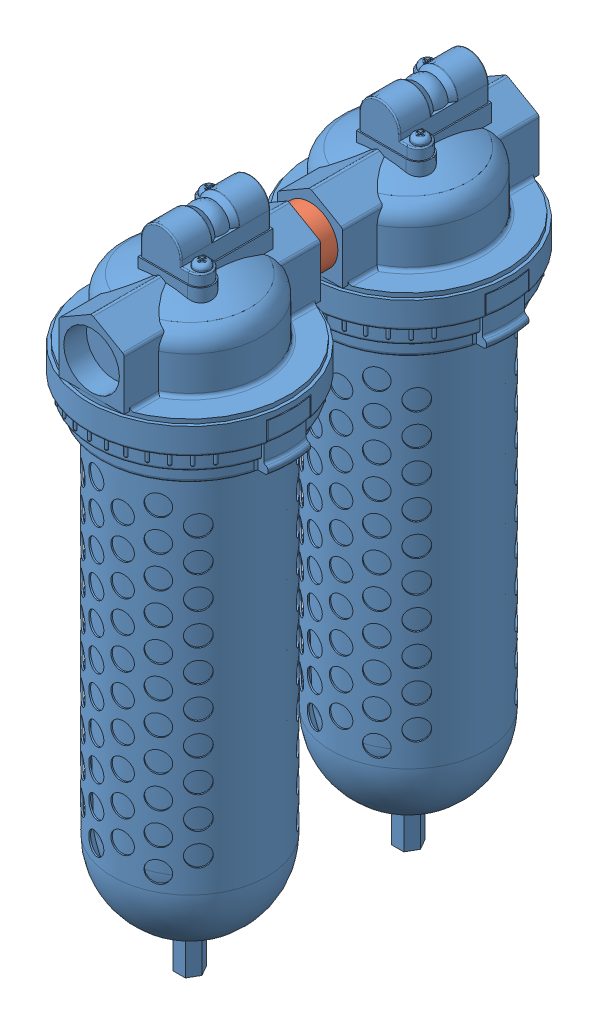
SolidWorks assembly ReadingTech_4P-150-P08-DCi, configuration Default. Lengths in mm.
Overall size (121.86 394.5 252.73).
3 component instances, 2 part files, 3 mates.
Components (placement in the parent):
- ReadingTech_3P150P08Fi-1: ReadingTech_3P150P08Fi [Default] at (-33.0885 -215.021 -0.1977) size (121.86 394.5 121.67)
- ReadingTech_3P150P08Fi-2: ReadingTech_3P150P08Fi [Default] at (-33.0885 -215.021 -131.2617) size (121.86 394.5 121.67)
- ReadingTech- 90,150cfm_connector_1in-1: ReadingTech- 90,150cfm_connector_1in [Default] at (-33.0885 173.98 -59.1257) x (1 0 0) z (0 1 0) size (33.4 13.21 33.4)
Mates (geometry in assembly coordinates):
- Coincident1: coincident anti-aligned: circle of ReadingTech_3P150P08Fi-2; circle of ReadingTech- 90,150cfm_connector_1in-1
- Coincident2: coincident aligned: circle of ReadingTech_3P150P08Fi-1; circle of ReadingTech- 90,150cfm_connector_1in-1
- Coincident3: coincident aligned: plane of ReadingTech_3P150P08Fi-1 through (-13.5305 186.68 58.7303) normal (1 0 0); plane of ReadingTech_3P150P08Fi-2 through (-13.5305 186.68 -72.3337) normal (1 0 0)
